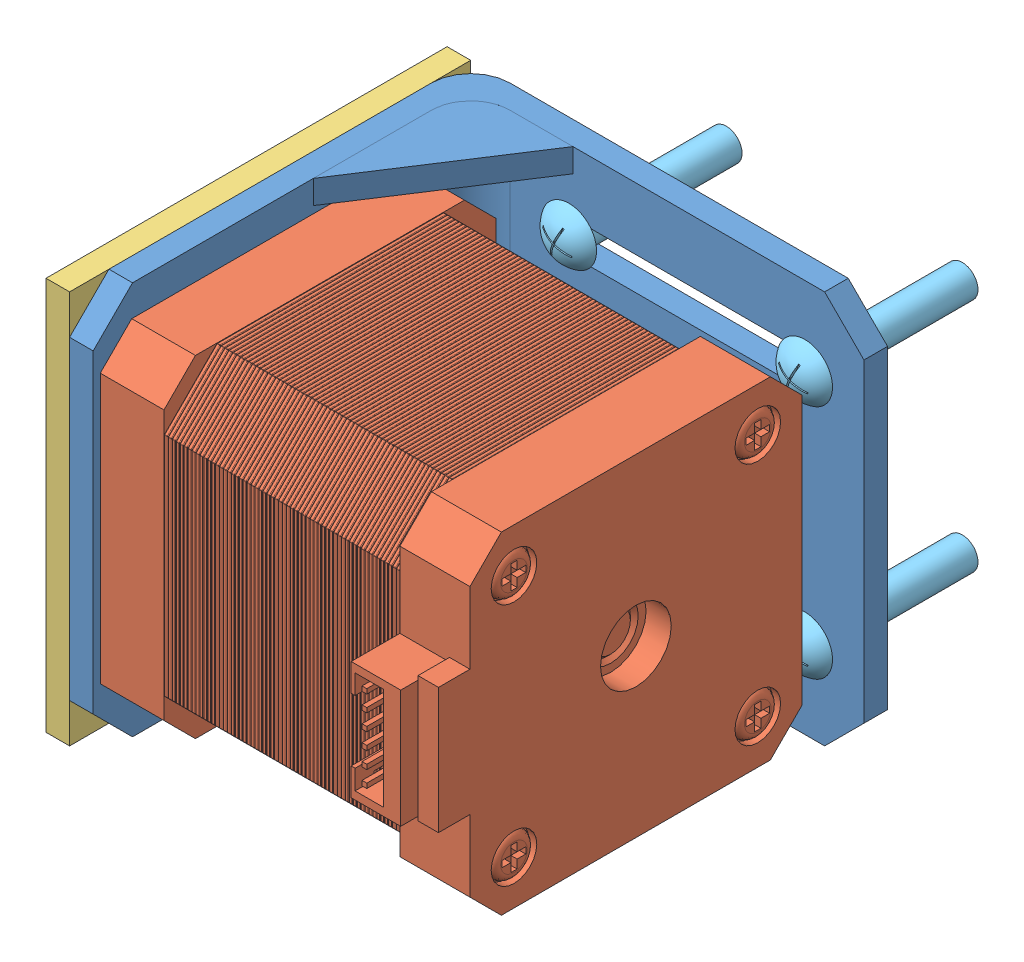
SolidWorks assembly Motor con base, configuration Predeterminado. Lengths in mm.
Overall size (70.5 50 73.3).
11 component instances, 5 part files, 11 mates.
Components (placement in the parent):
- soporte-1: soporte [Predeterminado] at (-53.4895 15.589 -25.5) size (53 50 51)
- Nema17-1: Nema17 [Default] at (-3.4895 -9.411 3.5) x (0 0 1) z (0 -1 0) size (48.4 67.5 42.2)
- Cara motor-1: Cara motor [Predeterminado] at (-53.4895 15.589 -25.5) x (0 0 1) z (-1 0 0) size (51 50 3)
- M3_10mm-1: M3_10mm [Predeterminado] at (-46.4895 -24.911 19) x (0 -0.647004 -0.762487) z (1 0 0) size (4 4 11.5)
- M3_10mm-2: M3_10mm [Predeterminado] at (-46.4895 6.2099 18.8791) x (0 -0.762487 0.647004) z (1 0 0) size (4 4 11.5)
- M3_10mm-3: M3_10mm [Predeterminado] at (-46.4895 6.089 -12.2418) x (0 0.647004 0.762487) z (1 0 0) size (4 4 11.5)
- M3_10mm-4: M3_10mm [Predeterminado] at (-46.4895 -25.0319 -12.1209) x (0 0.762487 -0.647004) z (1 0 0) size (4 4 11.5)
- M4_20mm-1: M4_20mm [Predeterminado] at (-7.9895 -24.411 -42.5) x (0.921394 -0.38863 0) z (0 0 -1) size (7 7 22)
- M4_20mm-2: M4_20mm [Predeterminado] at (-37.9895 -24.411 -42.5) x (0.921394 -0.38863 0) z (0 0 -1) size (7 7 22)
- M4_20mm-3: M4_20mm [Predeterminado] at (-7.9895 5.589 -42.5) x (0.921394 -0.38863 0) z (0 0 -1) size (7 7 22)
- M4_20mm-4: M4_20mm [Predeterminado] at (-37.9895 5.589 -42.5) x (0.921394 -0.38863 0) z (0 0 -1) size (7 7 22)
Mates (geometry in assembly coordinates):
- Concéntrica1: concentric anti-aligned: circle of nema17-mount.step-1; circle of Nema17-1
- Concéntrica2: concentric anti-aligned: circle of nema17-mount.step-1; circle of Nema17-1
- Coincidente1: coincident anti-aligned: plane of soporte-1 through (-50.4895 15.589 -17.5) normal (1 0 0); plane of Nema17-1 through (-50.4895 -9.411 3.5) normal (-1 0 0)
- EnPosición1: in place: plane of soporte-1 through (-53.4895 15.589 25.5) normal (-1 0 0); plane of ? through (-53.4895 0 0) normal (-1 0 0); moOrthogonalPlaneRef_w of soporte-1 through (-53.4895 15.589 25.5) normal (-1 0 0); plane of ? through (-53.4895 0 0) normal (0 1 0); plane of soporte-1 through (-53.4895 15.589 25.5) normal (-1 0 0); plane of ? through (-53.4895 0 0) normal (0 0 1); plane of soporte-1 through (-53.4895 15.589 25.5) normal (-1 0 0); unknown of Cara motor-1
- Coincidente2: coincident aligned: plane of ?; plane of ?
- Coincidente3: coincident aligned: moOrthogonalPlaneRef_w of soporte-1 through (-53.4895 15.589 -25.5) normal (0 1 0); plane of Pieza2^Motor con base-1 through (-53.4895 15.589 -25.5) normal (0 1 0)
- Coincidente4: coincident anti-aligned: moOrthogonalPlaneRef_w of soporte-1 through (-53.4895 15.589 -25.5) normal (0 0 -1); plane of Pieza2^Motor con base-1 through (-53.4895 15.589 -25.5) normal (0 0 1)
- Concéntrica3: concentric aligned: cylinder of Cara motor-1 through (-56.4895 -24.911 19) axis (1 0 0) radius 1.75; cylinder of M3_10mm-1 through (-56.4895 -24.911 19) axis (1 0 0) radius 1.5
- Coincidente5: coincident anti-aligned: plane of Cara motor-1 through (-56.4895 15.589 -25.5) normal (-1 0 0); circle of M3_10mm-1
- Concéntrica4: concentric anti-aligned: cylinder of soporte-1 through (-7.9895 -24.411 -22.5) axis (0 0 1) radius 2.1; cylinder of M4_20mm-1 through (-7.9895 -24.411 -22.5) axis (0 0 -1) radius 2
- Coincidente6: coincident anti-aligned: plane of soporte-1 through (-0.4895 15.589 -22.5) normal (0 0 1); plane of M4_20mm-1 through (-4.7646 -25.7712 -22.5) normal (0 0 -1)
